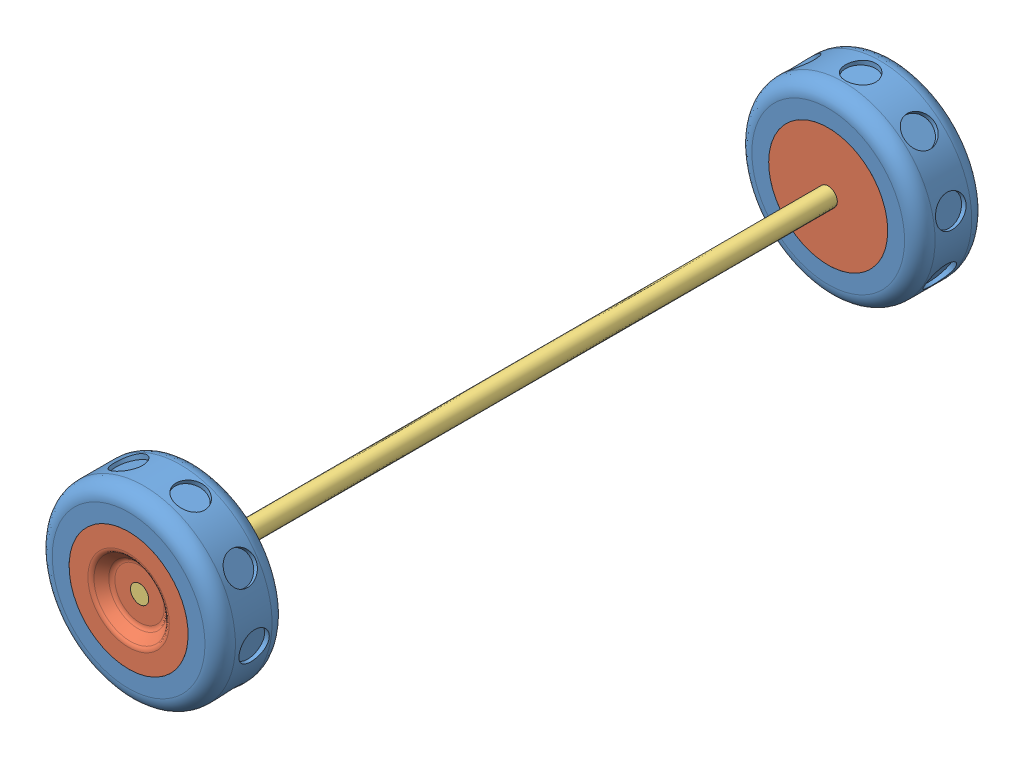
SolidWorks assembly Assem1, configuration Default. Lengths in mm.
Overall size (78.41 78.41 251.2).
7 component instances, 3 part files, 4 mates.
Components (placement in the parent):
- Wheel_Assembly-1: Wheel_Assembly [Default] at (17.2762 1.443 -10.0968) size (60 60 22)
  - Wheel_External-1: Wheel_External [Default] at (-0.9064 32.1198 46.8024) size (60 60 22)
  - Wheel_Ring-1: Wheel_Ring [Default] at (-0.9064 32.1198 57.8024) size (39 39 22)
- Wheel_Axle-1: Wheel_Axle [Default] at (16.3698 33.5629 40.3056) x (0 0 1) z (-1 0 0) size (244 6 6)
- Wheel_Assembly-2: Wheel_Assembly [Default] at (27.836 3.5457 334.7079) x (-0.923728 -0.383049 0) z (0 0 -1) size (60 60 22)
  - Wheel_External-1: Wheel_External [Default] at (-0.9064 32.1198 46.8024) size (60 60 22)
  - Wheel_Ring-1: Wheel_Ring [Default] at (-0.9064 32.1198 57.8024) size (39 39 22)
Mates (geometry in assembly coordinates):
- Coincident1: coincident aligned: plane of Wheel_Assembly-1/Wheel_Ring-1 through (16.3698 33.5629 40.3056) normal (0 0 -1); plane of Wheel_Axle-1 through (16.3698 33.5629 40.3056) normal (0 0 -1)
- Concentric2: concentric anti-aligned: cylinder of Wheel_Assembly-1/Wheel_Ring-1 through (16.3698 33.5629 36.7056) axis (0 0 1) radius 3; cylinder of Wheel_Axle-1 through (16.3698 33.5629 284.3056) axis (0 0 -1) radius 3
- Coincident2: coincident aligned: plane of Wheel_Axle-1 through (16.3698 33.5629 284.3056) normal (0 0 1); plane of Wheel_Assembly-2/Wheel_Ring-1 through (16.3698 33.5629 284.3056) normal (0 0 1)
- Concentric3: concentric aligned: cylinder of Wheel_Axle-1 through (16.3698 33.5629 284.3056) axis (0 0 -1) radius 3; cylinder of Wheel_Assembly-2/Wheel_Ring-1 through (16.3698 33.5629 287.9056) axis (0 0 -1) radius 3
